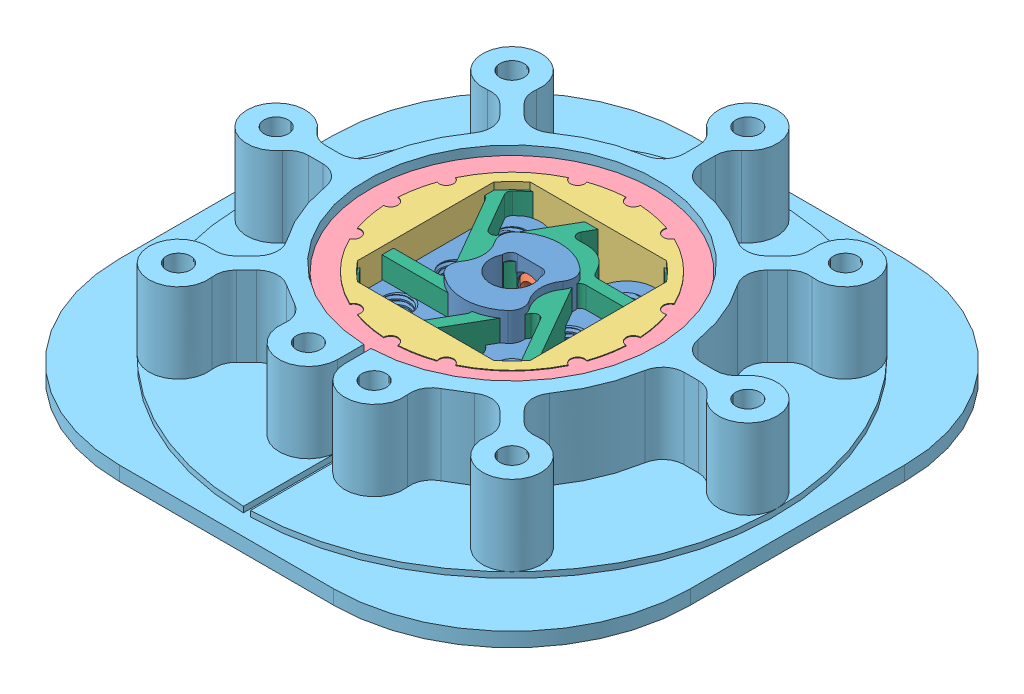
SolidWorks assembly wheel-tire-mold, configuration Default. Lengths in mm.
Overall size (80 14 80).
8 component instances, 6 part files, 6 mates.
Components (placement in the parent):
- wheel-40mm-gobilda-hub-1: wheel-40mm-gobilda-hub [Default] at origin size (40 11 40) (hidden)
  - 1308-0016-1006 assembly-1: 1308-0016-1006 assembly [Default] at (-6.1581 7.9163 -4.9236) size (24 8.14 24)
    - 1308-0016-1006-1: 1308-0016-1006 [Default] at (6.1581 -15.9163 4.9236) size (24 8.14 24)
    - 2806-0005-0004_91390A117-1: 2806-0005-0004_91390A117 [Default] at (6.1581 -11.9163 0.032) x (-0.598774 -0.800918 0) z (0 0 -1) size (5.13 5 4.14)
  - rim^wheel-40mm-gobilda-hub-1: rim^wheel-40mm-gobilda-hub [Default] at origin size (34.17 11 34.17) (virtual)
  - tire^wheel-40mm-gobilda-hub-1: tire^wheel-40mm-gobilda-hub [Default] at origin size (40 10.8 40) (virtual)
- mold^wheel-tire-mold-1: mold^wheel-tire-mold [Default] at origin size (80 14 80) (virtual)
- wheel-hub-v3-1: wheel-hub-v3 [Default] at (0 -11 0) x (1 0 0) z (0 1 0) size (40 40 10)
Mates (geometry in assembly coordinates):
- Coincident3: coordinate: point of wheel-40mm-gobilda-hub-1
- Coincident4: coordinate: unknown of mold^wheel-tire-mold-1
- Coincident5: coordinate: unknown of wheel-mold-dissolvable^wheel-tire-mold-1
- Coincident6: coincident anti-aligned: plane of mold^wheel-tire-mold-1 through (0 -11 0) normal (0 1 0); plane of wheel-hub-v3-1 through (0 -11 0) normal (0 -1 0)
- Coincident7: coincident anti-aligned: line of mold^wheel-tire-mold-1 through (8 0 -8) axis (0 0 1); line of wheel-hub-v3-1 through (10 0 -1) axis (0 0 -1)
- Coincident8: coincident anti-aligned: plane of wheel-hub-v3-1 through (0 -11 0) normal (0 0 -1)
